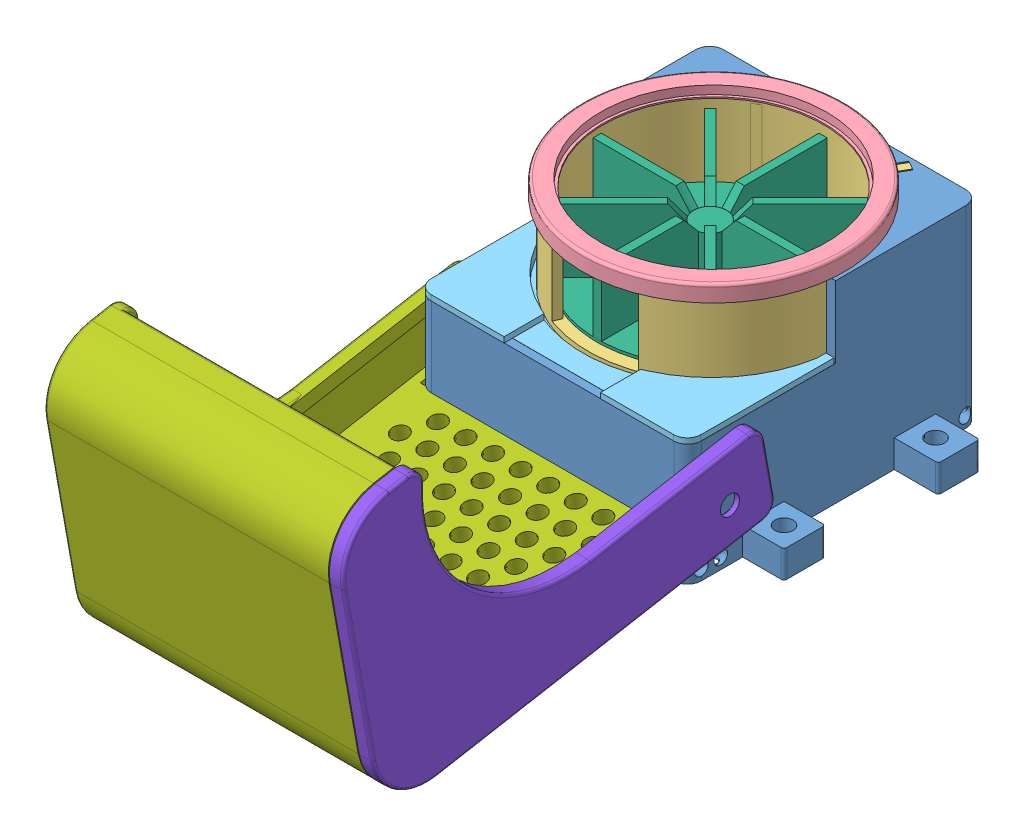
SolidWorks assembly Final Assembly, configuration Default. Lengths in mm.
Overall size (130.31 124.04 260.24).
8 component instances, 8 part files, 13 mates.
Components (placement in the parent):
- Case-1: Case [Default] at (33.3907 15.4696 91.0404) size (129 70 108.48)
- Servo (motor)-1: Servo (motor) [Default] at (29.8063 17.4696 86.3404) x (0 0 1) z (-1 0 0) size (20 46 41)
- Shell-1: Shell [Default] at (33.7532 57.5171 85.9744) x (0.866025 0 -0.5) z (0.5 0 0.866025) size (91.69 32 97.97)
- Shell lid-1: Shell lid [Default] at (33.7532 89.5171 85.9744) x (0.872184 0 -0.489178) z (0.489178 0 0.872184) size (95 6 95)
- Case lid-2: Case lid [Default] at (94.4264 55.5171 90.1823) size (98 6 102.03)
- carousel-1: carousel [Default] at (33.3396 60.3142 86.7996) size (82 27 82)
- Tray Left (main)-1: Tray Left (main) [Default] at (88.3907 29.1074 203.2981) x (-1 0 0) z (0 0.176156 -0.984362) size (103 100 145.35)
- Tray Right (edge)-1: Tray Right (edge) [Default] at (88.7885 29.1074 203.2981) x (-1 0 0) z (0 0.176156 -0.984362) size (9 100 145.35)
Mates (geometry in assembly coordinates):
- Coincident1: coincident: plane of Case-1 through (43.3872 22.4696 96.4404) normal (-1 0 0); plane of Servo (motor)-1 through (43.3872 57.4696 76.3404) normal (1 0 0)
- Coincident2: coincident: plane of Case-1 through (2.2872 22.4696 76.3404) normal (0 0 1); plane of Servo (motor)-1 through (43.3872 57.4696 76.3404) normal (0 0 -1)
- Coincident3: coincident: plane of Case-1 through (33.3907 17.4696 91.0404) normal (0 1 0); plane of Servo (motor)-1 through (29.8063 17.4696 86.3404) normal (0 -1 0)
- Coincident6: coincident: plane of Case-1 through (58.1419 55.4696 39.464) normal (-0.5 0 0.866025); plane of Shell-1 through (61.289 57.5171 41.281) normal (0.5 0 -0.866025)
- Coincident7: coincident: plane of Case-1 through (8.6325 55.4696 39.464) normal (-0.866025 0 0.5); plane of Shell-1 through (8.8155 57.5171 39.781) normal (0.866025 0 -0.5)
- Coincident19: coincident: plane of Case-1 through (79.3907 59.4696 41.0404) normal (-1 0 0); plane of Case lid-2 through (79.3907 59.5171 41.0404) normal (1 0 0)
- Coincident20: coincident: plane of Case-1 through (-12.6093 59.4696 141.0404) normal (0 0 -1); plane of Case lid-2 through (-7.6093 59.5171 141.0404) normal (0 0 1)
- Coincident39: coincident: plane of Shell-1 through (33.7532 57.5171 85.9744) normal (0 -1 0); plane of Case lid-2 through (33.3872 57.5171 86.3404) normal (0 1 0)
- Concentric1: concentric: cylinder of Shell-1 through (33.7532 89.5171 85.9744) axis (0 -1 0) radius 42.5; cylinder of Shell lid-1 through (33.7532 85.5171 85.9744) axis (0 1 0) radius 45.7
- Concentric2: concentric: circle of Case-1; circle of Tray Right (edge)-1
- Concentric3: concentric: circle of Case-1; circle of Tray Left (main)-1
- Coincident43: coincident: plane of Case-1 through (-15.6093 17.4696 144.0404) normal (-1 0 0); plane of Tray Left (main)-1 through (-15.6093 -37.3799 92.303) normal (1 0 0)
- Coincident45: coincident: plane of Tray Left (main)-1 through (-21.6093 112.7782 218.2714) normal (0 0.984362 0.176156); plane of Tray Right (edge)-1 through (-21.2115 112.7782 218.2714) normal (0 0.984362 0.176156)
